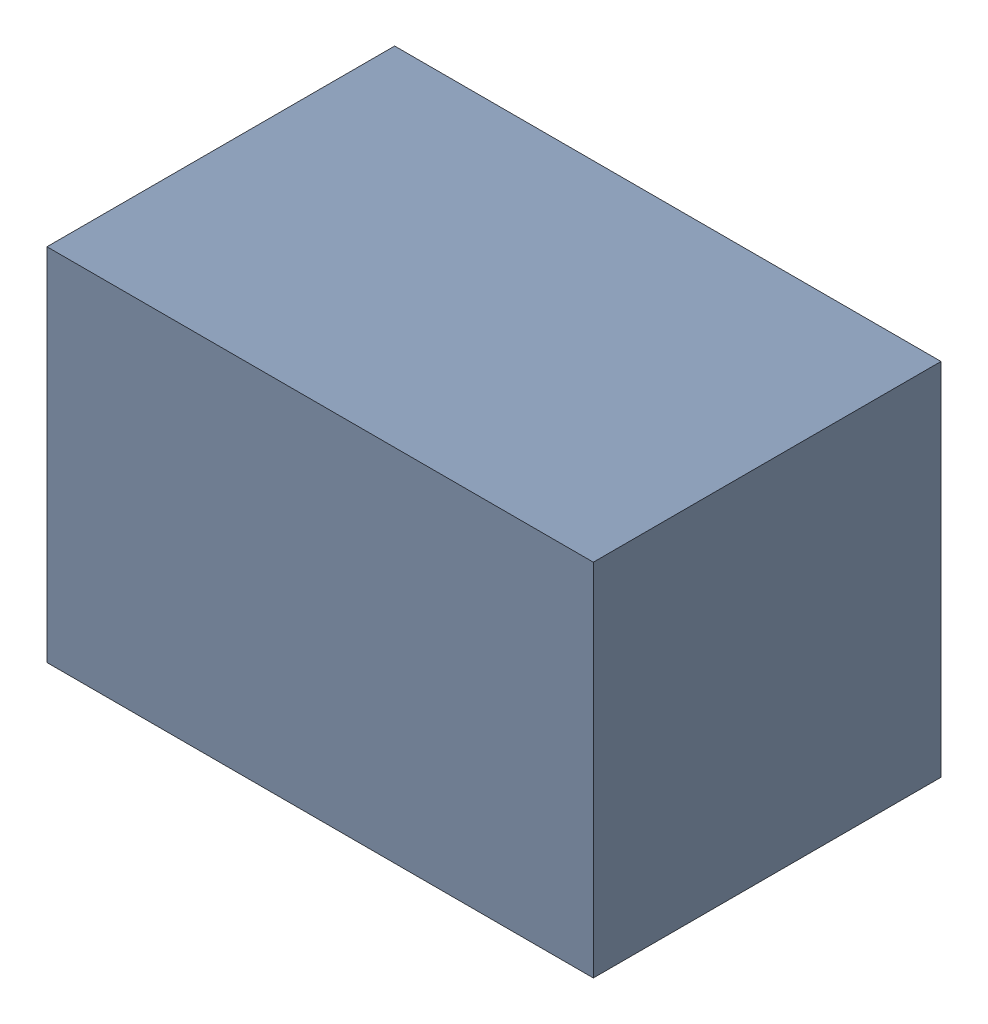
SolidWorks assembly C22, configuration Default. Lengths in mm.
Overall size (2.2 1.45 1.4).
2 component instances, 1 part files, 0 mates.
Components (placement in the parent):
- 1017092848-1: 1017092848 [Default] at (127 144.78 0) size (2.2 1.45 1.4)
  - Extruded_3-1: Extruded_3 [Default] at origin size (2.2 1.45 1.4)
